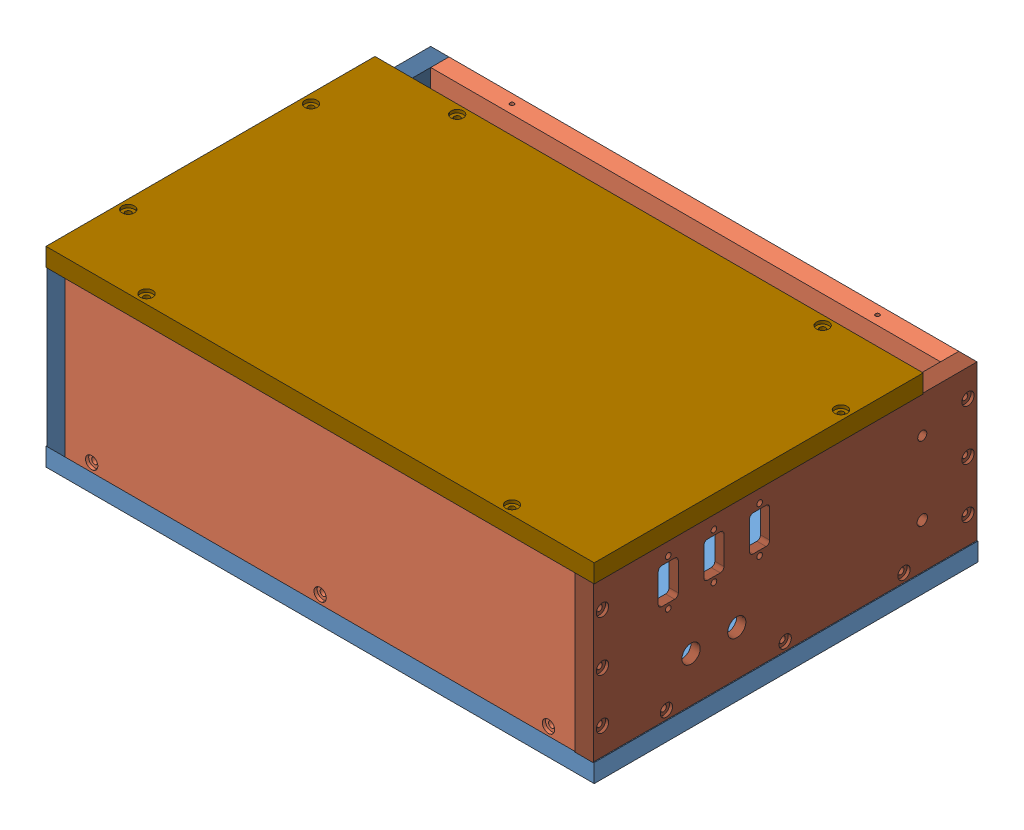
SolidWorks assembly outer_box_assem, configuration Default. Lengths in mm.
Overall size (300 104.64 210).
41 component instances, 30 part files, 33 mates.
Components (placement in the parent):
- outer_base-1: outer_base [Default] at (135.3772 124.8718 257.2403) size (300 19.28 210)
- outer_wall_sides-3: outer_wall_sides [Default] at (121.0167 141.479 164.7277) x (-1 0 0) z (0 0 -1) size (279 85 10)
- outer_wall_sides-4: outer_wall_sides [Default] at (104.0091 141.479 354.7277) size (279 85 10)
- innerbox_assembly-1: innerbox_assembly [Default] at (232.8953 37.1063 443.1681) x (-1 0 0) z (0 0 -1) size (234.23 274.82 264.79)
  - laser_cavity1-1: laser_cavity1 [Default] at (-6.1956 108.4655 167.017) size (190 60 150)
  - waveplate_mount-1: waveplate_mount [Default] at (135.4806 137.7657 203.4402) x (-0.017452 0 0.999848) z (-0.999848 0 -0.017452) size (19.15 29.88 9.04)
  - fiberport-1: fiberport [Default] at (96.9604 137.7854 203.4216) x (0 0 1) z (-1 0 0) size (28.58 38.1 18.91)
  - waveplate_mount-2: waveplate_mount [Default] at (160.7358 137.7657 203.4408) x (0.018746 0 -0.999824) z (0.999824 0 0.018746) size (19.15 29.88 9.04)
  - waveplate_mount-4: waveplate_mount [Default] at (152.6735 137.7657 143.4409) x (0.034899 0 -0.999391) z (0.999391 0 0.034899) size (19.15 29.88 9.04)
  - PBS122-Solidworks-3: PBS122-Solidworks [Default] at (180.3294 137.7655 143.6155) x (-0.017452 0 0.999848) z (0.999848 0 0.017452) size (12.7 12.7 12.7)
  - diode-3: diode [Default] at (49.1324 137.7655 143.4404) x (0 0 -1) z (1 0 0) size (38.9 25.4 20.95)
  - iris_assem-1: iris_assem [Default] at (98.8828 111.0503 160.8731) x (0 0 -1) z (1 0 0) size (38 35 31.31)
    - aperture_stand-1: aperture_stand [Default] at (24.6565 7.4152 58.0556) size (38 35 19.5)
    - pinhole plate-1: pinhole plate [Default] at (8.8041 16.6677 31.9348) size (29.9 20 5)
    - iris_SM05D5D-Solidworks-1: iris_SM05D5D-Solidworks [Web Assembly] at (17.5327 26.6677 41.9579) x (0.828172 -0.560474 0) z (0 0 -1) size (18.41 18.41 12.06)
  - collimation_len_assem-4: collimation_len_assem [Default] at (77.8982 167.3981 112.1366) x (-1 0 0) z (0 0 1) size (13.84 40 39)
    - collimation lens plate-1: collimation lens plate [Default] at (10.0158 38.6264 34.7131) size (10 40 39)
    - collimation_lens_adapter-1: collimation_lens_adapter [Default] at (16.5233 29.6326 31.3038) x (0 0 -1) z (1 0 0) size (26.29 26.29 6.99)
    - collimation_lens-1: collimation_lens [Default] at (6.1728 29.6326 31.3038) size (6.86 12.24 12.24)
  - fiber_P5-630PMR-P01-1-Solidworks-1: fiber_P5-630PMR-P01-1-Solidworks [Default] at (-426.526 137.7854 203.4216) x (0 0 -1) z (1 0 0) size (9.99 9.99 53.66)
  - photodiode_FDS1010-Solidworks-1: photodiode_FDS1010-Solidworks [Default] at (180.43 134.2853 112.6881) x (0.997257 0 0.074015) z (0 -1 0) size (11.43 0.89 26.42)
  - mounted_piezo_mirror-2: mounted_piezo_mirror [Default] at (194.8264 123.8869 196.8986) x (0.707107 0 0.707107) z (-0.707107 0 0.707107) size (89.59 24.89 24.89)
    - ST05-F3H_mirror_mount-1: ST05-F3H_mirror_mount [Default] at (15.6025 13.8786 15.9598) x (0 0 -1) z (1 0 0) size (24.89 24.89 23.61)
    - piezo_adapter-1: piezo_adapter [Default] at (3.7285 13.8786 15.9598) x (0 0.985412 -0.170186) z (0 -0.170186 -0.985412) size (12.7 4 12.7)
    - PK25LA2P2-piezo-1: PK25LA2P2-piezo [Default] at (-3.8016 13.8786 15.9598) x (0 0.259713 -0.965686) z (0 -0.965686 -0.259713) size (8.2 68.55 11.43)
    - BB03-E03-Solidworks-1: BB03-E03-Solidworks [Default] at (-5.3017 13.8786 15.9598) x (0 0.942622 0.333863) z (1 0 0) size (7 7 2)
  - TEC-1: TEC [Default] at (177.6772 106.0455 135.6448) size (50 3.42 50)
  - TEC-2: TEC [Default] at (162.7222 106.0455 204.6448) size (50 3.42 50)
  - TEC-3: TEC [Default] at (93.6895 106.0455 135.6448) size (50 3.42 50)
  - telescope_assem-2: telescope_assem [Default] at (86.5777 110.3062 113.6158) size (25 25.3 38)
    - telescope_stand-1: telescope_stand [Default] at (18495.2515 8.1592 11328.0159) size (25 17 38)
    - cyl_lens_concave-2: cyl_lens_concave [Default] at (21.3841 27.4592 29.848) x (0 1 0) z (1 0 0) size (8 4 3.16)
    - cylindricalconvex_LJ1960L1-B-Solidworks-1: cylindricalconvex_LJ1960L1-B-Solidworks [Default] at (5.6598 27.4592 29.8856) x (0 1 0) z (-1 0 0) size (12 10 3.29)
  - fiber_bed_lid-1: fiber_bed_lid [Default] at (104.1524 129.4466 253.4404) x (1 0 0) z (0 -1 0) size (134.9 5 44.5)
  - PBS_clamppost_PM3-Solidworks-2: PBS_clamppost_PM3-Solidworks [Default] at (188.1682 143.1 127.7678) x (-0.529039 0 0.848597) z (-0.848597 0 -0.529039) size (29.19 36.45 10.26)
  - inner_lid-2: inner_lid [Default] at (118.8385 163.4655 164.4702) x (1 0 -0.000004) z (0.000004 0 1) size (180 5 150)
  - virtual_alignment_tool-1: virtual_alignment_tool [Default] at (-20.2234 137.8198 143.6154) size (300 1 101) (hidden)
  - virtual_alignment_tool-2: virtual_alignment_tool [Default] at (181.3458 137.8198 203.2816) x (-1 0 0) z (0 0 -1) size (300 1 101) (hidden)
- outer_lid-1: outer_lid [Default] at (90.8735 219.5118 262.4326) size (300 10 180)
- outer_wall_front-2: outer_wall_front [Default] at (-36.9871 61.1486 246.5691) x (0 -1 0) z (1 0 0) size (85 210 10)
- outer_wall_electronics-4: outer_wall_electronics [Default] at (262.0129 61.1486 272.8863) x (0 -1 0) z (-1 0 0) size (85 210 10)
Mates (geometry in assembly coordinates):
- Coincident1: coincident anti-aligned: plane of outer_base-1 through (135.3772 134.8718 257.2403) normal (0 1 0); plane of outer_wall_electronics-1 through (262.5129 134.8718 335.7998) normal (0 -1 0)
- Coincident2: coincident anti-aligned: plane of outer_base-1 through (252.5129 144.1518 164.7277) normal (1 0 0); plane of outer_wall_electronics-1 through (252.5129 293.235 243.9584) normal (-1 0 0)
- Coincident3: coincident: plane of outer_base-1 through (135.3772 134.8718 257.2403) normal (0 1 0); plane of outer_wall_sides-1 through (-27.4871 134.8718 334.7277) normal (0 -1 0)
- Coincident4: coincident anti-aligned: plane of outer_base-1 through (-27.4871 144.1518 354.7277) normal (0 0 1); plane of outer_wall_sides-1 through (103.5091 126.839 324.7277) normal (0 0 -1)
- Coincident5: coincident anti-aligned: plane of outer_base-1 through (135.3772 134.8718 257.2403) normal (0 1 0); plane of outer_wall_sides-2 through (-129.7879 134.8718 164.7277) normal (0 -1 0)
- Coincident6: coincident anti-aligned: plane of outer_base-1 through (-27.4871 144.1518 164.7277) normal (0 0 -1); plane of outer_wall_sides-2 through (1.2083 126.839 164.7277) normal (0 0 1)
- Concentric1: concentric: circle of outer_base-1; circle of outer_wall_electronics-2
- Concentric2: concentric: circle of outer_base-1; circle of outer_wall_electronics-2
- Coincident7: coincident anti-aligned: plane of outer_base-1 through (252.5129 144.1518 164.7277) normal (1 0 0); plane of outer_wall_electronics-2 through (252.5129 46.1486 242.6363) normal (-1 0 0)
- Concentric3: concentric: circle of outer_base-1; circle of outer_wall_sides-1
- Concentric4: concentric aligned: circle of outer_base-1; circle of outer_wall_sides-3
- Concentric5: concentric aligned: circle of outer_base-1; circle of outer_wall_sides-3
- Coincident8: coincident anti-aligned: plane of outer_base-1 through (-27.4871 144.1518 164.7277) normal (0 0 -1); plane of outer_wall_sides-3 through (121.0167 141.479 164.7277) normal (0 0 1)
- Concentric6: concentric: circle of outer_base-1; circle of outer_wall_front-1
- Concentric7: concentric: circle of outer_base-1; circle of outer_wall_front-1
- Coincident9: coincident anti-aligned: plane of outer_base-1 through (-27.4871 144.1518 164.7277) normal (-1 0 0); plane of outer_wall_front-1 through (-27.4871 46.1486 246.8191) normal (1 0 0)
- Concentric8: concentric anti-aligned: circle of outer_base-1; circle of innerbox_assembly-1/laser_cavity1-1
- Concentric9: concentric aligned: circle of outer_base-1; circle of innerbox_assembly-1/laser_cavity1-1
- Concentric10: concentric aligned: circle of outer_base-1; circle of outer_wall_sides-4
- Concentric11: concentric anti-aligned: circle of outer_base-1; circle of outer_wall_sides-4
- Coincident10: coincident anti-aligned: plane of outer_base-1 through (-27.4871 144.1518 354.7277) normal (0 0 1); plane of outer_wall_sides-4 through (104.0091 141.479 354.7277) normal (0 0 -1)
- Concentric12: concentric anti-aligned: circle of outer_base-1; circle of innerbox_assembly-1/laser_cavity1-1
- Concentric13: concentric anti-aligned: circle of outer_base-1; circle of innerbox_assembly-1/laser_cavity1-1
- Coincident11: coincident anti-aligned: plane of outer_base-1 through (135.3772 143.1518 257.2403) normal (0 1 0); plane of innerbox_assembly-1/TEC-2 through (70.1731 143.1518 238.5233) normal (0 -1 0)
- Concentric14: concentric aligned: circle of outer_lid-1; circle of outer_wall_sides-4
- Concentric15: concentric aligned: circle of outer_lid-1; circle of outer_wall_sides-4
- Coincident12: coincident anti-aligned: plane of outer_wall_sides-4 through (-26.9871 219.5118 364.7277) normal (0 1 0); plane of outer_lid-1 through (90.8735 219.5118 262.4326) normal (0 -1 0)
- Concentric16: concentric aligned: circle of outer_wall_sides-4; circle of outer_wall_electronics-4
- Concentric17: concentric aligned: circle of outer_wall_sides-4; circle of outer_wall_electronics-4
- Coincident13: coincident anti-aligned: plane of outer_wall_sides-4 through (252.0129 219.5118 364.7277) normal (1 0 0); plane of outer_wall_electronics-4 through (252.0129 61.1486 272.8863) normal (-1 0 0)
- Concentric18: concentric aligned: circle of outer_wall_sides-4; circle of outer_wall_front-2
- Concentric19: concentric aligned: circle of outer_wall_sides-4; circle of outer_wall_front-2
- Coincident14: coincident anti-aligned: plane of outer_wall_sides-4 through (-26.9871 219.5118 364.7277) normal (-1 0 0); plane of outer_wall_front-2 through (-26.9871 61.1486 246.5691) normal (1 0 0)
